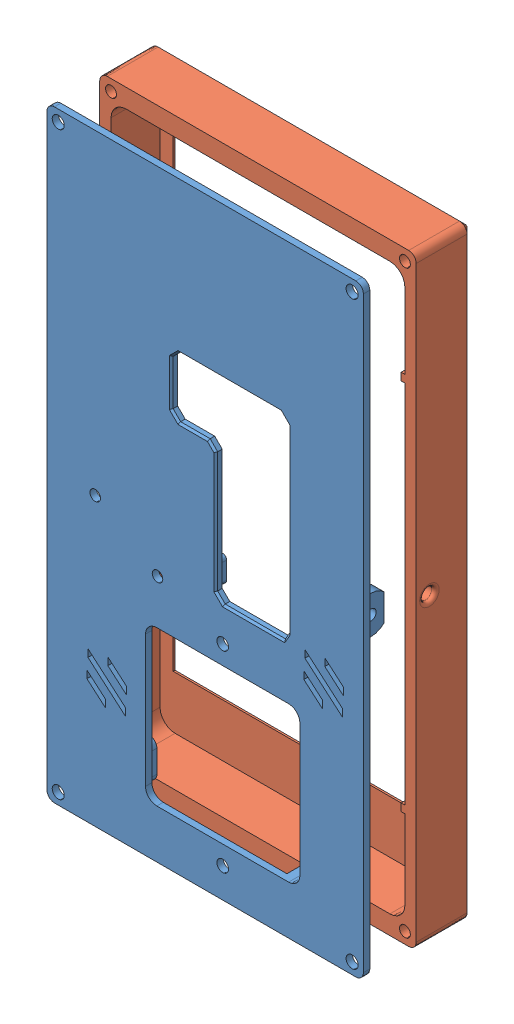
SolidWorks assembly comp, configuration 默认. Lengths in mm.
Overall size (84 160 29.01).
2 component instances, 2 part files, 2 mates.
Components (placement in the parent):
- lower_shell-2: lower_shell [默认] at (255.6622 -1392.4701 12.8994) size (84 160 8.7)
- upper_shell-1: upper_shell [默认] at (-8.0408 -1423.1618 -14.4156) x (1 0 0) z (0 -1 0) size (84 15 160)
Mates (geometry in assembly coordinates):
- 同心1: concentric: cylinder of assembly; cylinder of assembly; cylinder of lower_shell-2 through (69.9592 -77 8.3739) axis (0 0 1) radius 1.6; cylinder of upper_shell-1 through (69.9592 -77 -16.5168) axis (0 0 1) radius 1.45
- 同心2: concentric: cylinder of assembly; cylinder of assembly; cylinder of lower_shell-2 through (-8.0408 77 8.3739) axis (0 0 1) radius 1.6; cylinder of upper_shell-1 through (-8.0408 77 -16.5168) axis (0 0 1) radius 1.45
